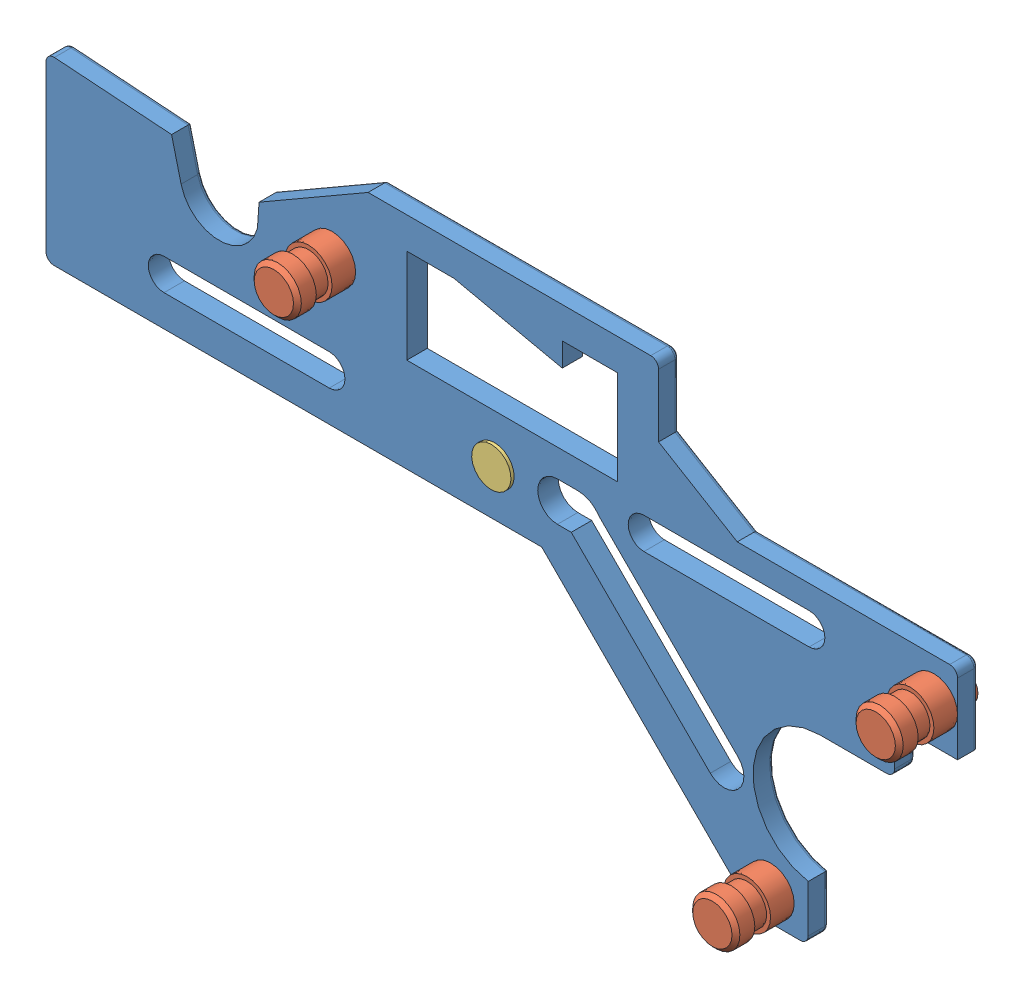
SolidWorks assembly Assemblage2, configuration Défaut. Lengths in mm.
Overall size (115.86 55.31 11.5).
5 component instances, 3 part files, 8 mates.
Components (placement in the parent):
- Pièce8-1: Pièce8 [Défaut] at (-51.9489 -2.022 0) size (115.86 54.87 2.63)
- Pièce9-1: Pièce9 [Défaut] at (-15.5889 16.4069 10) x (0 0 -1) z (1 0 0) size (11 6 6)
- Pièce9-2: Pièce9 [Défaut] at (60.9111 5.978 10) x (0 0 -1) z (1 0 0) size (11 6 6)
- Pièce9-3: Pièce9 [Défaut] at (40.1491 -25.25 10) x (0 0 -1) z (0.486722 0.873557 0) size (11 6 6)
- Pièce10-1: Pièce10 [Défaut] at (5.0511 3.978 -1.5) x (0 0 1) z (-1 0 0) size (4.5 8 8)
Mates (geometry in assembly coordinates):
- Coaxiale1: concentric anti-aligned: cylinder of Pièce8-1 through (-15.5889 16.4069 0) axis (0 0 1) radius 2; cylinder of Pièce9-1 through (-15.5889 16.4069 -1) axis (0 0 -1) radius 2
- Coïncidente1: coincident anti-aligned: plane of Pièce8-1 through (-37.5769 17.9681 2.6) normal (0 0 1); plane of Pièce9-1 through (-15.5889 19.4069 2.6) normal (0 0 -1)
- Coïncidente2: coincident anti-aligned: cylinder of Pièce8-1 through (60.9111 5.978 0) axis (0 0 1) radius 2; circle of Pièce9-2
- Coïncidente3: coincident anti-aligned: plane of Pièce8-1 through (-37.5769 17.9681 2.6) normal (0 0 1); circle of Pièce9-2
- Coïncidente4: coincident anti-aligned: circle of Pièce8-1; cylinder of Pièce9-3 through (40.1491 -25.25 -1) axis (0 0 -1) radius 2
- Coïncidente5: coincident anti-aligned: plane of Pièce8-1 through (-37.5769 17.9681 2.6) normal (0 0 1); circle of Pièce9-3
- Coïncidente6: coincident aligned: circle of Pièce8-1; cylinder of Pièce10-1 through (5.0511 3.978 3) axis (0 0 1) radius 2.5
- Coïncidente7: coincident anti-aligned: plane of Pièce8-1 through (-37.5769 17.9681 0) normal (0 0 -1); circle of Pièce10-1
